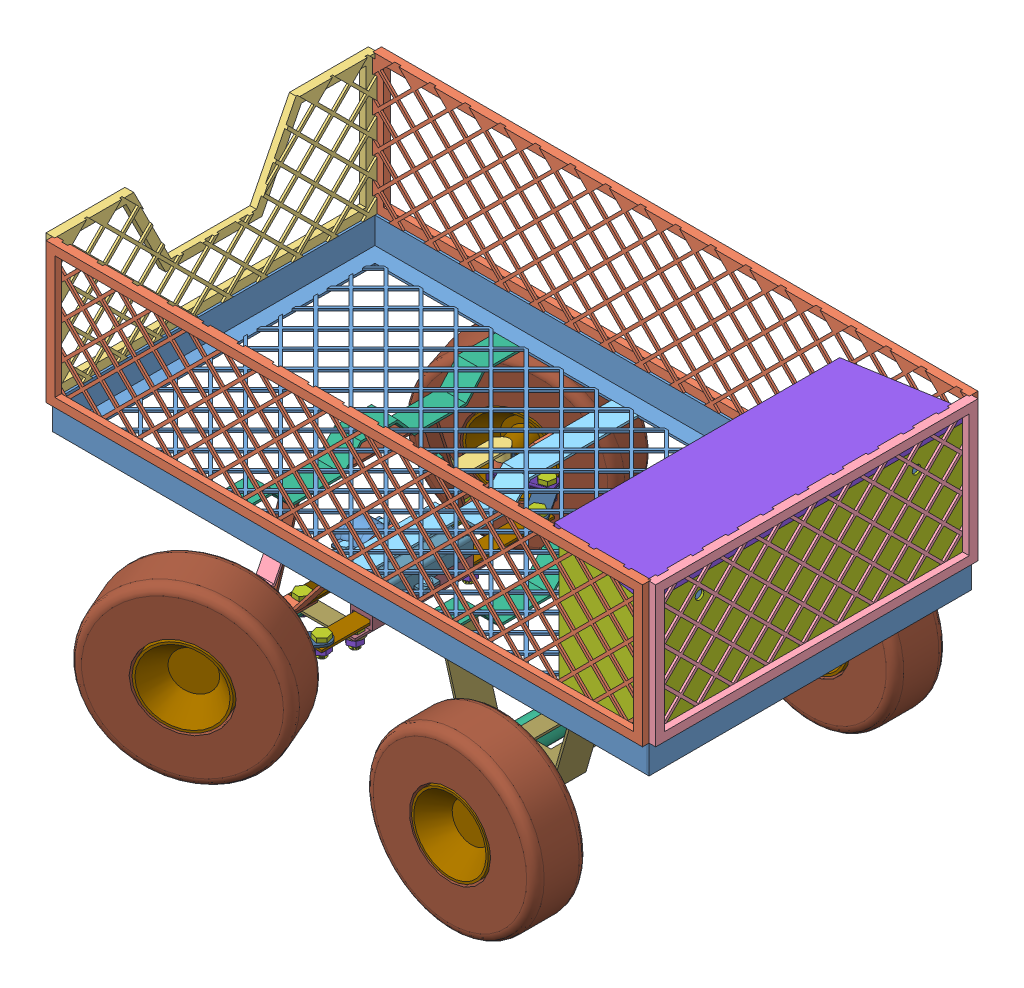
SolidWorks assembly BaseBot, configuration Default. Lengths in mm.
Overall size (882.65 573.45 703.44).
132 component instances, 48 part files, 93 mates.
Components (placement in the parent):
- Basket Bottom-1: Basket Bottom [Default] at (255.4338 0 27.1639) x (1 0 0) z (0 1 0) size (863.6 466.73 41.27)
- Basket Side-1: Basket Side [Default] at (387.544 20.0282 -463.55) x (0 0 -1) z (1 0 0) size (12.7 203.2 863.6)
- Basket Side-2: Basket Side [Default] at (213.6348 20.0282 -3.175) x (0 0 1) z (-1 0 0) size (12.7 203.2 863.6)
- Basket Front-2: Basket Front [Default] at (-128.0356 170.1145 -302.8358) x (-1 0 0) z (0 0 -1) size (12.7 203.2 466.73)
- Basket Back-1: Basket Back [Default] at (741.9144 37.962 -98.425) x (-1 0 0) z (0 0 1) size (12.7 203.2 466.73)
- BaseBot Support Bar #2-2: BaseBot Support Bar #2 [Default] at (237.0894 -11.8301 -299.0589) x (1 0 0) z (0 0 -1) size (38.1 28.57 419.1)
- BaseBot Support Bar #1-2: BaseBot Support Bar #1 [Default] at (68.8144 0 -270.0364) x (1 0 0) z (0 0 -1) size (38.1 32.02 419.1)
- BaseBot Support Bar #1-3: BaseBot Support Bar #1 [Default] at (370.4394 0 -270.0364) x (1 0 0) z (0 0 -1) size (38.1 32.02 419.1)
- BaseBot Support Bar #1-4: BaseBot Support Bar #1 [Default] at (579.9894 0 -270.0364) x (1 0 0) z (0 0 -1) size (38.1 32.02 419.1)
- Steering Mechanism-2: Steering Mechanism [Default] at (175.5898 -169.9237 -213.8762) x (0 0 -1) z (1 0 0) size (542.29 220.93 188.26)
  - Pinon Gear-1: Pinon Gear [Default] at (18.0596 23.4154 -25.5289) x (0.999971 0.007586 0) z (0 0 1) size (28.79 28.79 12.7)
  - 37d-gearmotor-100-131-150-encoder-1: 37d-gearmotor-100-131-150-encoder [Default] at (-1.8654 30.4154 -54.9751) size (36.8 36.8 90.1)
  - Rack-1: Rack [Default] at (-58.7281 -0.9127 -25.3751) x (0.965926 -0.258819 0) z (0 0 1) size (326.19 90.25 25.4)
  - Control Arm-1: Control Arm [Default] at (-149.1406 7.5404 -13.7125) x (-0.583389 0 0.812193) z (0 1 0) size (25.4 76.2 3.17)
  - Control Arm-2: Control Arm [Default] at (205.3106 7.5404 -41.201) x (-0.549424 0 -0.835544) z (0 1 0) size (25.4 76.2 3.17)
  - Front Wheel Bracket-1: Front Wheel Bracket [Default] at (7.9885 116.6287 -76.1751) x (1 0 0) z (0 0 -1) size (292.1 146.24 25.4)
  - Short Rack Support Structure-1: Short Rack Support Structure [Default] at (83.7255 -5.1596 -55.7455) x (-1 0 0) z (0 -1 0) size (25.4 101.6 3.17)
  - Short Rack Support Structure-2: Short Rack Support Structure [Default] at (-59.553 -5.1596 -45.8047) x (1 0 0) z (0 -1 0) size (25.4 101.6 3.17)
  - Long Rack Support Structure-2: Long Rack Support Structure [Default] at (-38.0612 -5.1596 -14.7918) x (0 1 0) z (1 0 0) size (26.76 57.15 190.5)
  - Long Rack Support Structure (Top)-1: Long Rack Support Structure (Top) [Default] at (37.6137 21.6016 3.1999) x (-1 0 0) z (0 0 -1) size (146.05 23.59 57.15)
  - Pivot Arm (Left)-2: Pivot Arm (Left) [Default] at (-186.8809 -11.5096 -33.1605) x (-0.541489 0 0.840708) z (-0.840708 0 -0.541489) size (96.16 53.98 123.84)
  - Pivot Arm (Right)-2: Pivot Arm (Right) [Default] at (211.0535 -8.3346 -33.1605) x (0.541489 0 0.840708) z (0.840708 0 -0.541489) size (104.82 53.97 137.29)
  - Front Wheel Axles-3: Front Wheel Axles [Default] at (277.9295 11.2102 -114.4995) x (-0.310493 0 -0.950576) z (-0.950576 0 0.310493) size (76.2 13.19 76.21)
  - Steering Motor Mount (Bottom)-2: Steering Motor Mount (Bottom) [Default] at (15.3381 12.3464 -101.5751) x (0 0 1) z (-1 0 0) size (78.58 31.27 183.81)
  - Steering Motor Mount (Top)-2: Steering Motor Mount (Top) [Default] at (19.4781 29.2864 -76.1751) x (0 0 -1) z (1 0 0) size (78.58 22.18 69.09)
  - Front Wheel Axles-4: Front Wheel Axles [Default] at (-240.1244 10.2206 -69.4744) x (-0.399781 0 -0.916611) z (0.916611 0 -0.399781) size (76.2 13.19 76.21)
  - Spacer-1: Spacer [Default] at (229.822 -8.3346 -95.0926) x (0.991664 0 -0.128853) z (0.128853 0 0.991664) size (19.05 12.7 19.05)
  - Spacer-2: Spacer [Default] at (-178.3747 -8.3346 -100.4751) x (0.523364 0 -0.852109) z (0.852109 0 0.523364) size (19.05 12.7 19.05)
  - Spacer-3: Spacer [Default] at (-169.1502 17.0654 -93.7664) size (19.05 12.7 19.05)
  - Spacer-4: Spacer [Default] at (230.5407 17.0654 -93.7664) size (19.05 12.7 19.05)
  - Front Wheel Support-1: Front Wheel Support [Default] at (127.4023 52.8952 -76.1751) x (-0.999975 0.007006 0) z (0 0 -1) size (101.09 57.73 25.4)
  - Front Wheel Support #2-1: Front Wheel Support #2 [Default] at (-103.2542 52.8183 -101.5751) x (0.999975 0.007006 0) z (0 0 1) size (85.09 57.73 25.4)
  - 0.25in Hex Bolt-1: 0.25in Hex Bolt [Default] at (1.5398 307.5194 143.5864) x (-0.430629 -0.859999 0.273788) z (0.894165 -0.447737 0) size (11.2 12.9 19.05)
  - 0.25in Hex Bolt-2: 0.25in Hex Bolt [Default] at (-17.0641 387.1538 -112.045) x (0.261641 -0.522518 -0.811491) z (-0.894165 -0.447737 0) size (11.2 12.9 19.05)
  - 0.25in Nut-1: 0.25in Nut [Default] at (125.0268 72.0692 -88.8751) x (0.297793 -0.594716 -0.746748) z (0.894165 0.447737 0) size (12.9 11.18 6.49)
  - 0.25in Nut-2: 0.25in Nut [Default] at (-101.1354 72.1209 -88.8751) x (0.403858 0.806536 0.431739) z (-0.894165 0.447737 0) size (12.9 11.18 6.49)
  - 0.25in Hex Bolt-3: 0.25in Hex Bolt [Default] at (-118.1926 35.6364 214.9281) x (-0.491617 0 -0.870811) z (0 -1 0) size (11.2 12.9 19.05)
  - 0.25in Hex Bolt-4: 0.25in Hex Bolt [Default] at (4.4078 28.1666 355.6025) x (-0.837169 0 -0.546944) z (0 -1 0) size (11.2 12.9 19.05)
  - 0.25in Hex Bolt-5: 0.25in Hex Bolt [Default] at (-36.5422 28.1666 311.1525) x (-0.837169 0 -0.546944) z (0 -1 0) size (11.2 12.9 19.05)
  - 0.25in Hex Bolt-6: 0.25in Hex Bolt [Default] at (-16.1952 35.6364 257.1775) x (-0.837169 0 -0.546944) z (0 -1 0) size (11.2 12.9 19.05)
  - 0.25in Hex Bolt-7: 0.25in Hex Bolt [Default] at (52.3578 28.1666 311.1525) x (-0.837169 0 -0.546944) z (0 -1 0) size (11.2 12.9 19.05)
  - 0.25in Nut-3: 0.25in Nut [Default] at (47.6747 21.5662 -88.8751) x (0.781177 0 -0.624309) z (0 1 0) size (12.9 11.18 6.49)
  - 0.25in Nut-4: 0.25in Nut [Default] at (59.8346 11.8571 -34.9001) x (1 0 0) z (0 1 0) size (12.9 11.18 6.49)
  - 0.25in Nut-5: 0.25in Nut [Default] at (11.8846 11.8554 9.5499) x (1 0 0) z (0 1 0) size (12.9 11.18 6.49)
  - 0.25in Nut-6: 0.25in Nut [Default] at (-29.0654 11.8571 -34.9001) x (1 0 0) z (0 1 0) size (12.9 11.18 6.49)
  - 0.25in Nut-7: 0.25in Nut [Default] at (-8.7184 21.5662 -88.8751) x (1 0 0) z (0 1 0) size (12.9 11.18 6.49)
  - 0.5in Hex Bolt-1: 0.5in Hex Bolt [Default] at (235.7047 23.4154 -40.5859) x (0.98122 0 0.192894) z (0 -1 0) size (22 19.05 28.57)
  - 0.5in Hex Bolt-2: 0.5in Hex Bolt [Default] at (193.2591 17.0654 -12.6751) x (1 0 0) z (0 -1 0) size (22 19.05 28.57)
  - 0.5in Hex Bolt-3: 0.5in Hex Bolt [Default] at (-70.3463 7.5404 -88.8751) x (-0.837169 0 -0.546944) z (0 -1 0) size (22 19.05 28.57)
  - 0.5in Hex Bolt-4: 0.5in Hex Bolt [Default] at (94.7596 4.3654 -12.6751) x (1 0 0) z (0 -1 0) size (22 19.05 28.57)
  - 0.5in Hex Bolt-5: 0.5in Hex Bolt [Default] at (94.7596 7.5404 -88.8751) x (0.964084 0 0.265597) z (0 -1 0) size (22 19.05 28.57)
  - 0.5in Hex Bolt-6: 0.5in Hex Bolt [Default] at (-70.3404 4.3654 -12.6751) x (0.999732 0 0.023139) z (0 -1 0) size (22 19.05 28.57)
  - 0.5in Hex Bolt-7: 0.5in Hex Bolt [Default] at (-118.1909 17.0654 -12.6751) x (0.969144 0 -0.246494) z (0 -1 0) size (22 19.05 28.57)
  - 0.5in Hex Bolt-8: 0.5in Hex Bolt [Default] at (-159.4503 23.4154 -42.3113) x (-0.837169 0 -0.546944) z (0 -1 0) size (22 19.05 28.57)
  - 0.5in Nut-1: 0.5in Nut [Default] at (193.2591 4.3654 -12.6751) x (1 0 0) z (0 -1 0) size (21.73 20.53 9.68)
  - 0.5in Nut-2: 0.5in Nut [Default] at (-159.4503 -5.1596 -42.3113) x (1 0 0) z (0 1 0) size (21.73 20.53 9.68)
  - 0.5in Nut-3: 0.5in Nut [Default] at (-70.3404 -17.8596 -12.6751) x (1 0 0) z (0 1 0) size (21.73 20.53 9.68)
  - 0.5in Nut-4: 0.5in Nut [Default] at (235.7047 -5.1596 -40.5859) x (1 0 0) z (0 1 0) size (21.73 20.53 9.68)
  - 0.5in Nut-5: 0.5in Nut [Default] at (94.7596 -21.0346 -88.8751) x (-0.015272 0 -0.999883) z (0 1 0) size (21.73 20.53 9.68)
  - 0.5in Nut-6: 0.5in Nut [Default] at (94.7596 -17.8596 -12.6751) x (1 0 0) z (0 1 0) size (21.73 20.53 9.68)
  - 0.5in Nut-7: 0.5in Nut [Default] at (-118.1909 4.3654 -12.6751) x (1 0 0) z (0 -1 0) size (21.73 20.53 9.68)
  - 0.5in Nut-8: 0.5in Nut [Default] at (-70.3463 -17.8596 -88.8751) x (1 0 0) z (0 1 0) size (21.73 20.53 9.68)
- Hub-10: Hub [Default] at (123.8857 -159.7031 66.9915) x (-0.399781 0 -0.916611) z (-0.916611 0 0.399781) size (88.9 111.12 111.12)
- Hub-11: Hub [Default] at (47.2889 -158.7135 -534.0588) x (0.310493 0 0.950576) z (-0.950576 0 0.310493) size (88.9 111.12 111.12)
- Radial Ball Bearing 17mm Bore-1: Radial Ball Bearing 17mm Bore [Default] at (74.8917 -158.7135 -449.5527) x (0 1 0) z (-0.950576 0 0.310493) size (34 12 34)
- Radial Ball Bearing 17mm Bore-2: Radial Ball Bearing 17mm Bore [Default] at (88.3451 -159.7031 -14.4951) x (0 -1 0) z (-0.916611 0 0.399781) size (34 12 34)
- Wheel-10: Wheel [Default] at (176.9035 -109.9016 43.8677) x (-0.399781 0 -0.916611) z (-0.91661 -0.000518 0.399781) size (76.2 247.65 247.65)
- Wheel-11: Wheel [Default] at (69.4962 -231.3772 -541.3125) x (0.310493 0 0.950576) z (-0.810689 0.522172 0.264801) size (76.2 247.65 247.65)
- Back Wheel Housing-4: Back Wheel Housing [Default] at (588.3026 -7.0122 -438.4176) x (-1 0 0) z (0 0 1) size (246.62 123.18 406.4)
- Gearbox-1: Gearbox [Default] at (568.39 -299.7014 -139.8553) x (-1 0 0) z (0 1 0) size (101.63 50.81 63.71)
  - Gearbox Bottom-1: Gearbox Bottom [Default] at (74.587 76.0877 168.5715) size (101.6 28.57 63.5)
  - Gearbox - 12T-1: Gearbox - 12T [Default] at (92.1067 91.9627 143.3599) x (0.92261 0 -0.385735) z (0 1 0) size (23.03 23.03 12.7)
  - Gearbox - 24T-1: Gearbox - 24T [Default] at (61.1138 91.9627 144.7723) x (1 0 0) z (0 1 0) size (43.72 43.72 12.7)
  - Gearbox - 12T-2: Gearbox - 12T [Default] at (122.4014 91.9627 144.7942) x (1 0 0) z (0 -1 0) size (23.03 23.03 12.7)
  - Gearbox - 24T-2: Gearbox - 24T [Default] at (92.1067 79.2627 143.3599) x (0.834365 0 -0.551212) z (0 1 0) size (43.72 43.72 12.7)
  - R155-2RS Mini ball Bearing-1: R155-2RS Mini ball Bearing [Default] at (92.1067 95.0377 143.3599) x (1 0 0) z (0 0 -1) size (7.94 3.17 7.94)
  - R155-2RS Mini ball Bearing-2: R155-2RS Mini ball Bearing [Default] at (61.1138 95.0377 144.7723) x (1 0 0) z (0 0 -1) size (7.94 3.17 7.94)
  - R155-2RS Mini ball Bearing-3: R155-2RS Mini ball Bearing [Default] at (92.1067 104.7627 143.3599) x (0.999892 0 0.014713) z (0.014713 0 -0.999892) size (7.94 3.17 7.94)
  - R155-2RS Mini ball Bearing-4: R155-2RS Mini ball Bearing [Default] at (61.1138 104.7627 144.7723) x (1 0 0) z (0 0 -1) size (7.94 3.17 7.94)
  - R155-2RS Mini ball Bearing-5: R155-2RS Mini ball Bearing [Default] at (122.4014 79.1627 144.7942) size (7.94 3.17 7.94)
  - R155-2RS Mini ball Bearing-6: R155-2RS Mini ball Bearing [Default] at (92.1067 82.3377 143.3599) x (1 0 0) z (0 0 -1) size (7.94 3.17 7.94)
  - R155-2RS Mini ball Bearing-7: R155-2RS Mini ball Bearing [Default] at (122.4014 92.0627 144.7942) x (1 0 0) z (0 0 -1) size (7.94 3.17 7.94)
  - R155-2RS Mini ball Bearing-8: R155-2RS Mini ball Bearing [Default] at (92.1067 92.0627 143.3599) x (1 0 0) z (0 0 -1) size (7.94 3.17 7.94)
  - 2in Axle-2: 2in Axle [Default] at (122.4014 104.655 144.7942) x (0.232669 0 0.972556) z (0 -1 0) size (3.97 3.97 38.1)
  - 2in Axle-3: 2in Axle [Default] at (61.1138 79.2627 144.7723) x (0.898573 0 0.438824) z (0 1 0) size (3.97 3.97 38.1)
  - 1in Axle-1: 1in Axle [Default] at (92.1067 79.2627 143.3599) x (0.237926 0 -0.971283) z (0 1 0) size (3.97 3.97 25.4)
  - Gearbox Lid-1: Gearbox Lid [Default] at (121.6136 104.6627 145.3537) x (1 0 0) z (0 1 0) size (101.6 63.5 3.17)
  - 0.25in Hex Bolt-1: 0.25in Hex Bolt [Default] at (121.2528 111.0127 514.2191) x (-0.837169 0 -0.546944) z (0 -1 0) size (11.2 12.9 19.05)
  - 0.25in Hex Bolt-2: 0.25in Hex Bolt [Default] at (36.3678 111.0127 467.4391) x (-0.837169 0 -0.546944) z (0 -1 0) size (11.2 12.9 19.05)
- Front Wheel Brace-1: Front Wheel Brace [Default] at (133.8633 -17.6291 -360.0687) x (0 0 1) z (1 0 0) size (25.4 171.49 182.31)
- Front Wheel Brace-2: Front Wheel Brace [Default] at (133.8633 -17.6291 -135.4151) x (0 0 1) z (1 0 0) size (25.4 171.49 182.31)
- 37d-gearmotor-100-131-150-encoder-2: 37d-gearmotor-100-131-150-encoder [Default] at (425.8036 -148.6967 -112.0426) x (0.999225 0.039351 0) z (0 0 1) size (36.8 36.8 90.1)
- Motor to Axle Adapter-2: Motor to Axle Adapter [Default] at (445.9886 -154.9072 -70.1176) x (-0.999225 -0.039351 0) z (0 0 -1) size (12.34 12.34 19.05)
- Wheel to Axle Adapter-2: Wheel to Axle Adapter [Default] at (507.2762 -154.9291 -32.0176) x (-0.979173 -0.203029 0) z (0 0 1) size (14.7 14.7 50.8)
- Gearbox-3: Gearbox [Default] at (568.39 -10.1486 -330.5799) x (-1 0 0) z (0 -1 0) size (101.63 50.81 63.71)
  - Gearbox Bottom-1: Gearbox Bottom [Default] at (74.587 76.0877 168.5715) size (101.6 28.57 63.5)
  - Gearbox - 12T-1: Gearbox - 12T [Default] at (92.1067 91.9627 143.3599) x (0.92261 0 -0.385735) z (0 1 0) size (23.03 23.03 12.7)
  - Gearbox - 24T-1: Gearbox - 24T [Default] at (61.1138 91.9627 144.7723) x (1 0 0) z (0 1 0) size (43.72 43.72 12.7)
  - Gearbox - 12T-2: Gearbox - 12T [Default] at (122.4014 91.9627 144.7942) x (1 0 0) z (0 -1 0) size (23.03 23.03 12.7)
  - Gearbox - 24T-2: Gearbox - 24T [Default] at (92.1067 79.2627 143.3599) x (0.834365 0 -0.551212) z (0 1 0) size (43.72 43.72 12.7)
  - R155-2RS Mini ball Bearing-1: R155-2RS Mini ball Bearing [Default] at (92.1067 95.0377 143.3599) x (1 0 0) z (0 0 -1) size (7.94 3.17 7.94)
  - R155-2RS Mini ball Bearing-2: R155-2RS Mini ball Bearing [Default] at (61.1138 95.0377 144.7723) x (1 0 0) z (0 0 -1) size (7.94 3.17 7.94)
  - R155-2RS Mini ball Bearing-3: R155-2RS Mini ball Bearing [Default] at (92.1067 104.7627 143.3599) x (0.999892 0 0.014713) z (0.014713 0 -0.999892) size (7.94 3.17 7.94)
  - R155-2RS Mini ball Bearing-4: R155-2RS Mini ball Bearing [Default] at (61.1138 104.7627 144.7723) x (1 0 0) z (0 0 -1) size (7.94 3.17 7.94)
  - R155-2RS Mini ball Bearing-5: R155-2RS Mini ball Bearing [Default] at (122.4014 79.1627 144.7942) size (7.94 3.17 7.94)
  - R155-2RS Mini ball Bearing-6: R155-2RS Mini ball Bearing [Default] at (92.1067 82.3377 143.3599) x (1 0 0) z (0 0 -1) size (7.94 3.17 7.94)
  - R155-2RS Mini ball Bearing-7: R155-2RS Mini ball Bearing [Default] at (122.4014 92.0627 144.7942) x (1 0 0) z (0 0 -1) size (7.94 3.17 7.94)
  - R155-2RS Mini ball Bearing-8: R155-2RS Mini ball Bearing [Default] at (92.1067 92.0627 143.3599) x (1 0 0) z (0 0 -1) size (7.94 3.17 7.94)
  - 2in Axle-2: 2in Axle [Default] at (122.4014 104.655 144.7942) x (0.232669 0 0.972556) z (0 -1 0) size (3.97 3.97 38.1)
  - 2in Axle-3: 2in Axle [Default] at (61.1138 79.2627 144.7723) x (0.898573 0 0.438824) z (0 1 0) size (3.97 3.97 38.1)
  - 1in Axle-1: 1in Axle [Default] at (92.1067 79.2627 143.3599) x (0.237926 0 -0.971283) z (0 1 0) size (3.97 3.97 25.4)
  - Gearbox Lid-1: Gearbox Lid [Default] at (121.6136 104.6627 145.3537) x (1 0 0) z (0 1 0) size (101.6 63.5 3.17)
  - 0.25in Hex Bolt-1: 0.25in Hex Bolt [Default] at (121.2528 111.0127 514.2191) x (-0.837169 0 -0.546944) z (0 -1 0) size (11.2 12.9 19.05)
  - 0.25in Hex Bolt-2: 0.25in Hex Bolt [Default] at (36.3678 111.0127 467.4391) x (-0.837169 0 -0.546944) z (0 -1 0) size (11.2 12.9 19.05)
- Motor to Axle Adapter-4: Motor to Axle Adapter [Default] at (445.9886 -154.9428 -400.3176) x (0.99689 0.078808 0) z (0 0 1) size (12.34 12.34 19.05)
- Wheel to Axle Adapter-3: Wheel to Axle Adapter [Default] at (507.2762 -154.9209 -438.4176) x (-0.879655 -0.475613 0) z (0 0 -1) size (14.7 14.7 50.8)
- 37d-gearmotor-100-131-150-encoder-4: 37d-gearmotor-100-131-150-encoder [Default] at (465.6274 -147.176 -358.3236) x (-0.999249 -0.038749 0) z (0 0 -1) size (36.8 36.8 90.1)
- Hub-12: Hub [Default] at (507.2762 -154.9291 63.2324) x (0 0 -1) z (0.923728 0.383049 0) size (88.9 111.12 111.12)
- Hub-14: Hub [Default] at (507.2762 -154.9209 -533.6676) x (0 0 1) z (-0.923728 -0.383049 0) size (88.9 111.12 111.12)
- Radial Ball Bearing 17mm Bore-3: Radial Ball Bearing 17mm Bore [Default] at (507.2762 -154.9291 -25.6676) x (0.383049 -0.923728 0) z (-0.923728 -0.383049 0) size (34 12 34)
- Radial Ball Bearing 17mm Bore-4: Radial Ball Bearing 17mm Bore [Default] at (507.2762 -154.9209 -444.7676) x (-0.383049 0.923728 0) z (-0.923728 -0.383049 0) size (34 12 34)
- Wheel-12: Wheel [Default] at (557.4681 -97.4263 63.2324) x (0 0 -1) z (-0.989814 -0.142364 0) size (76.2 247.65 247.65)
- Wheel-13: Wheel [Default] at (579.7945 -178.7304 -533.6676) x (0 0 1) z (-0.923728 -0.383049 0) size (76.2 247.65 247.65)
- Back Motor Housing-1: Back Motor Housing [Default] at (450.0429 -135.0507 -328.9985) x (-1 0 0) z (0 0 -1) size (46.63 44.52 88.17)
- Back Motor Housing #2-1: Back Motor Housing #2 [Default] at (450.0429 -135.0507 -105.7116) x (-1 0 0) z (0 0 -1) size (46.63 44.52 88.17)
- Electronic Housing-1: Electronic Housing [Default] at (560.0657 6.35 -82.9961) x (0 1 0) z (0 0 -1) size (206.38 152.4 466.73)
- Electronic Housing  Lid-1: Electronic Housing  Lid [Default] at (654.5068 222.725 -248.6086) x (0 0 -1) z (-1 0 0) size (466.73 22.7 160.75)
- IMU Mount-1: IMU Mount [Default] at (620.5602 9.525 -235.0978) size (26.67 9.53 20.32)
- Mighty Max Battery 12V-1: Mighty Max Battery 12V [Default] at (734.3012 9.525 -312.8809) x (0 0 1) z (-1 0 0) size (181.1 166.88 76.45)
- Raspberry Pi Mount-1: Raspberry Pi Mount [Default] at (601.2449 9.525 -363.4658) x (0 1 0) z (0 0 1) size (15.88 49 85)
- Mighty Max Battery 12V-2: Mighty Max Battery 12V [Default] at (734.3012 9.525 -116.8985) x (0 0 1) z (-1 0 0) size (181.1 166.88 76.45)
- HBridge Mount-1: HBridge Mount [Default] at (610.79 9.525 -158.1025) x (0 0 -1) z (1 0 0) size (100 33.18 50)
Mates (geometry in assembly coordinates):
- Coincident4: coincident anti-aligned: plane of Basket Bottom-1 through (729.2144 41.275 -466.725) normal (0 1 0); plane of Basket Side-1 through (732.3894 41.275 -476.25) normal (0 -1 0)
- Coincident6: coincident aligned: plane of Basket Bottom-1 through (732.3894 3.175 -466.725) normal (1 0 0); plane of Basket Side-1 through (732.3894 244.475 -476.25) normal (1 0 0)
- Coincident7: coincident: line of Basket Bottom-1 through (-128.0356 41.275 -463.55) axis (1 0 0); plane of Basket Side-1 through (387.544 20.0282 -463.55) normal (0 0 1)
- Coincident8: coincident anti-aligned: plane of Basket Bottom-1 through (729.2144 41.275 -466.725) normal (0 1 0); plane of Basket Side-2 through (-131.2106 41.275 9.525) normal (0 -1 0)
- Coincident9: coincident aligned: plane of Basket Bottom-1 through (732.3894 3.175 -466.725) normal (1 0 0); plane of Basket Side-2 through (732.3894 244.475 9.525) normal (1 0 0)
- Coincident10: coincident: line of Basket Bottom-1 through (729.2144 41.275 -3.175) axis (-1 0 0); plane of Basket Side-2 through (213.6348 20.0282 -3.175) normal (0 0 -1)
- Coincident11: coincident anti-aligned: plane of Basket Bottom-1 through (729.2144 41.275 -466.725) normal (0 1 0); plane of Basket Front-2 through (-140.7356 41.275 0) normal (0 -1 0)
- Coincident12: coincident aligned: plane of Basket Bottom-1 through (-131.2106 3.175 0) normal (0 0 1); plane of Basket Front-2 through (-140.7356 244.475 0) normal (0 0 1)
- Coincident13: coincident: line of Basket Bottom-1 through (-128.0356 41.275 -3.175) axis (0 0 -1); plane of Basket Front-2 through (-128.0356 170.1145 -302.8358) normal (1 0 0)
- Coincident22: coincident anti-aligned: plane of Basket Bottom-1 through (729.2144 41.275 -466.725) normal (0 1 0); plane of Basket Back-1 through (729.2144 41.275 0) normal (0 -1 0)
- Coincident23: coincident aligned: plane of Basket Bottom-1 through (-131.2106 3.175 -466.725) normal (0 0 -1); plane of Basket Back-1 through (729.2144 41.275 -466.725) normal (0 0 -1)
- Coincident24: coincident: line of Basket Bottom-1 through (729.2144 41.275 -463.55) axis (0 0 1); plane of Basket Back-1 through (729.2144 37.962 -98.425) normal (-1 0 0)
- Parallel63: parallel aligned: plane of Basket Bottom-1 through (732.3894 3.175 -466.725) normal (1 0 0); plane of Basket Side-1 through (387.544 20.0282 -463.55) normal (1 0 0)
- Coincident313: coincident aligned: plane of Basket Bottom-1 through (-131.2106 3.175 0) normal (0 0 1)
- Coincident322: coincident: point of BaseBot Support Bar #2-2
- Coincident323: coincident: unknown of BaseBot Support Bar #1-2
- Coincident326: coincident: unknown of BaseBot Support Bar #1-3
- Coincident329: coincident: unknown of BaseBot Support Bar #1-4
- Coincident331: coincident anti-aligned: plane of Basket Bottom-1 through (255.4338 0 27.1639) normal (0 -1 0)
- Parallel69: parallel aligned: line of Basket Bottom-1 through (706.9894 0 -441.325) axis (-1 0 0); line of BaseBot Support Bar #1-4 through (618.0894 0 -444.5) axis (-1 0 0)
- Parallel70: parallel aligned: line of Basket Bottom-1 through (706.9894 0 -441.325) axis (-1 0 0); line of BaseBot Support Bar #1-3 through (408.5394 0 -444.5) axis (-1 0 0)
- Parallel71: parallel aligned: line of Basket Bottom-1 through (706.9894 0 -441.325) axis (-1 0 0); line of BaseBot Support Bar #2-2 through (275.1894 0 -444.5) axis (-1 0 0)
- Parallel72: parallel aligned: line of Basket Bottom-1 through (706.9894 0 -441.325) axis (-1 0 0); line of BaseBot Support Bar #1-2 through (106.9144 0 -444.5) axis (-1 0 0)
- Coincident336: coincident anti-aligned: plane of BaseBot Support Bar #1-2 through (106.9144 -28.8441 -184.15) normal (0 -1 0); plane of Steering Mechanism-2/Front Wheel Bracket-1 through (74.0147 -28.8441 -125.95) normal (0 1 0)
- Parallel73: parallel anti-aligned: line of BaseBot Support Bar #1-2 through (106.9144 -28.8441 -107.95) axis (0 0 -1); line of Steering Mechanism-2/Long Rack Support Structure (Top)-1 through (178.7897 -129.7321 -299.1108) axis (0 0 1)
- Coincident338: coincident: unknown of Steering Mechanism-2/Front Wheel Bracket-1
- Concentric1: concentric aligned: cylinder of Hub-10 through (93.4223 -159.7031 -2.8542) axis (0.399781 0 0.916611) radius 55.5625; cylinder of Wheel-10 through (93.4223 -159.7031 -2.8542) axis (0.399781 0 0.916611) radius 58.7375
- Coincident339: coincident aligned: plane of Hub-10 through (123.8857 -159.7031 66.9915) normal (0.399781 0 0.916611); plane of Wheel-10 through (123.8857 -159.7031 66.9915) normal (0.399781 0 0.916611)
- Concentric2: concentric anti-aligned: cylinder of Hub-10 through (88.3451 -159.7031 -14.4951) axis (0.399781 0 0.916611) radius 17; cylinder of Radial Ball Bearing 17mm Bore-2 through (93.1425 -159.7031 -3.4958) axis (-0.399781 0 -0.916611) radius 17
- Coincident340: coincident aligned: plane of Hub-10 through (88.3451 -159.7031 -14.4951) normal (-0.399781 0 -0.916611); plane of Radial Ball Bearing 17mm Bore-2 through (88.3451 -159.7031 -14.4951) normal (-0.399781 0 -0.916611)
- Concentric3: concentric aligned: cylinder of Hub-11 through (70.9485 -158.7135 -461.625) axis (-0.310493 0 -0.950576) radius 55.5625; cylinder of Wheel-11 through (70.9485 -158.7135 -461.625) axis (-0.310493 0 -0.950576) radius 58.7375
- Coincident341: coincident aligned: plane of Hub-11 through (47.2889 -158.7135 -534.0588) normal (-0.310493 0 -0.950576); plane of Wheel-11 through (47.2889 -158.7135 -534.0588) normal (-0.310493 0 -0.950576)
- Concentric4: concentric anti-aligned: cylinder of Hub-11 through (74.8917 -158.7135 -449.5527) axis (-0.310493 0 -0.950576) radius 17; cylinder of Radial Ball Bearing 17mm Bore-1 through (71.1658 -158.7135 -460.9596) axis (0.310493 0 0.950576) radius 17
- Coincident342: coincident aligned: plane of Hub-11 through (74.8917 -158.7135 -449.5527) normal (0.310493 0 0.950576); plane of Radial Ball Bearing 17mm Bore-1 through (74.8917 -158.7135 -449.5527) normal (0.310493 0 0.950576)
- Concentric5: concentric anti-aligned: cylinder of Steering Mechanism-2/Front Wheel Axles-4 through (85.8065 -159.7031 -20.3156) axis (0.399781 0 0.916611) radius 6.35; cylinder of Radial Ball Bearing 17mm Bore-2 through (93.1425 -159.7031 -3.4958) axis (-0.399781 0 -0.916611) radius 6.35
- Concentric6: concentric anti-aligned: cylinder of Steering Mechanism-2/Front Wheel Axles-3 through (76.8633 -158.7135 -443.5165) axis (-0.310493 0 -0.950576) radius 6.35; cylinder of Radial Ball Bearing 17mm Bore-1 through (71.1658 -158.7135 -460.9596) axis (0.310493 0 0.950576) radius 6.35
- Coincident344: coincident anti-aligned: plane of Steering Mechanism-2/Front Wheel Axles-3 through (61.0903 -158.7135 -491.8057) normal (-0.310493 0 -0.950576); plane of Hub-11 through (61.0903 -158.7135 -491.8057) normal (0.310493 0 0.950576)
- Coincident345: coincident aligned: circle of Steering Mechanism-2/Front Wheel Axles-4; plane of Hub-10 through (106.1154 -159.7031 26.2482) normal (-0.399781 0 -0.916611)
- Coincident348: coincident anti-aligned: plane of BaseBot Support Bar #1-4 through (618.0894 0 -444.5) normal (0 -1 0); plane of Back Wheel Housing-4 through (618.0894 0 -387.6176) normal (0 1 0)
- Coincident349: coincident aligned: line of BaseBot Support Bar #1-4 through (618.0894 0 -387.35) axis (0 0 -1); line of Back Wheel Housing-4 through (618.0894 0 -387.6176) axis (0 0 -1)
- Coincident355: coincident aligned: line of Back Wheel Housing-4 through (431.2799 -123.175 -32.0176) axis (0 0 -1); line of Gearbox-1/Gearbox Bottom-1 through (431.2799 -123.175 -35.1926) axis (0 0 -1)
- Coincident357: coincident anti-aligned: plane of Back Wheel Housing-4 through (558.2799 -123.175 -387.6176) normal (0 -1 0); plane of Gearbox-1/Gearbox Bottom-1 through (532.8799 -123.175 -60.5926) normal (0 1 0)
- Coincident358: coincident anti-aligned: line of Back Wheel Housing-4 through (431.2799 -123.175 -32.0176) axis (1 0 0); line of Gearbox-1/Gearbox Lid-1 through (532.9055 -123.175 -32.0176) axis (-1 0 0)
- Coincident364: coincident anti-aligned: plane of Steering Mechanism-2/Front Wheel Bracket-1 through (74.0147 -171.9083 -221.8647) normal (0 1 0); plane of Front Wheel Brace-1 through (99.4147 -171.9083 -334.6687) normal (0 -1 0)
- Parallel75: parallel anti-aligned: line of Steering Mechanism-2/Front Wheel Bracket-1 through (74.0147 -171.9083 -367.9797) axis (0 0 1); line of Front Wheel Brace-1 through (74.0147 -168.7333 -334.6687) axis (0 0 -1)
- Coincident366: coincident anti-aligned: line of Steering Mechanism-2/Front Wheel Bracket-1 through (74.0147 -171.9083 -367.9797) axis (0 0 1); line of Front Wheel Brace-1 through (74.0147 -171.9083 -334.6687) axis (0 0 -1)
- Coincident367: coincident anti-aligned: plane of Steering Mechanism-2/Front Wheel Bracket-1 through (74.0147 -171.9083 -221.8647) normal (0 1 0); plane of Front Wheel Brace-2 through (99.4147 -171.9083 -110.0151) normal (0 -1 0)
- Parallel76: parallel anti-aligned: line of Steering Mechanism-2/Front Wheel Bracket-1 through (74.0147 -171.9083 -152.9392) axis (0 0 1); line of Front Wheel Brace-2 through (74.0147 -168.7333 -110.0151) axis (0 0 -1)
- Coincident369: coincident anti-aligned: line of Steering Mechanism-2/Front Wheel Bracket-1 through (74.0147 -171.9083 -152.9392) axis (0 0 1); line of Front Wheel Brace-2 through (74.0147 -171.9083 -110.0151) axis (0 0 -1)
- Concentric8: concentric anti-aligned: cylinder of 37d-gearmotor-100-131-150-encoder-2 through (445.9886 -154.9072 -70.1176) axis (0 0 -1) radius 3; cylinder of Motor to Axle Adapter-2 through (445.9886 -154.9072 -82.8176) axis (0 0 1) radius 2.9972
- Parallel77: parallel anti-aligned: plane of 37d-gearmotor-100-131-150-encoder-2 through (445.8942 -152.5091 -82.1176) normal (-0.039351 0.999225 0); plane of Motor to Axle Adapter-2 through (445.8944 -152.5151 -82.8176) normal (0.039351 -0.999225 0)
- Coincident376: coincident aligned: plane of 37d-gearmotor-100-131-150-encoder-2 through (445.9886 -154.9072 -70.1176) normal (0 0 1); circle of Motor to Axle Adapter-2
- Concentric10: concentric anti-aligned: cylinder of Gearbox-1/2in Axle-2 through (445.9886 -154.9072 -73.3003) axis (0 0 1) radius 1.9844; cylinder of Motor to Axle Adapter-2 through (445.9886 -154.9072 -63.7676) axis (0 0 -1) radius 1.985
- Coincident378: coincident anti-aligned: plane of Gearbox-1/Gearbox Bottom-1 through (493.803 -131.1299 -63.7676) normal (0 0 -1); plane of Motor to Axle Adapter-2 through (445.9886 -154.9072 -63.7676) normal (0 0 1)
- Concentric15: concentric aligned: cylinder of Gearbox-1/2in Axle-3 through (507.2762 -154.9291 -22.4926) axis (0 0 -1) radius 1.9844; cylinder of Wheel to Axle Adapter-2 through (507.2762 -154.9291 -25.6676) axis (0 0 -1) radius 1.985
- Coincident388: coincident anti-aligned: plane of Gearbox-1/Gearbox Lid-1 through (446.7764 -154.3477 -32.0176) normal (0 0 1); plane of Wheel to Axle Adapter-2 through (507.2762 -154.9291 -32.0176) normal (0 0 -1)
- Coincident394: coincident anti-aligned: plane of Back Wheel Housing-4 through (558.2799 -123.175 -387.6176) normal (0 -1 0); plane of Gearbox-3/Gearbox Bottom-1 through (532.8799 -123.175 -409.8426) normal (0 1 0)
- Coincident395: coincident aligned: line of Back Wheel Housing-4 through (431.2799 -123.175 -438.4176) axis (1 0 0); line of Gearbox-3/Gearbox Lid-1 through (431.3055 -123.175 -438.4176) axis (1 0 0)
- Coincident396: coincident anti-aligned: line of Back Wheel Housing-4 through (431.2799 -123.175 -387.6176) axis (0 0 -1); line of Gearbox-3/Gearbox Bottom-1 through (431.2799 -123.175 -435.2426) axis (0 0 1)
- Concentric17: concentric anti-aligned: cylinder of Gearbox-3/2in Axle-2 through (445.9886 -154.9428 -397.1349) axis (0 0 -1) radius 1.9844; cylinder of Motor to Axle Adapter-4 through (445.9886 -154.9428 -406.6676) axis (0 0 1) radius 1.985
- Coincident397: coincident anti-aligned: plane of Gearbox-3/Gearbox Bottom-1 through (493.803 -178.7201 -406.6676) normal (0 0 1); plane of Motor to Axle Adapter-4 through (445.9886 -154.9428 -406.6676) normal (0 0 -1)
- Concentric18: concentric aligned: cylinder of Gearbox-3/2in Axle-3 through (507.2762 -154.9209 -447.9426) axis (0 0 1) radius 1.9844; cylinder of Wheel to Axle Adapter-3 through (507.2762 -154.9209 -444.7676) axis (0 0 1) radius 1.985
- Coincident398: coincident anti-aligned: plane of Gearbox-3/Gearbox Lid-1 through (446.7764 -155.5023 -438.4176) normal (0 0 -1); plane of Wheel to Axle Adapter-3 through (507.2762 -154.9209 -438.4176) normal (0 0 1)
- Concentric20: concentric anti-aligned: cylinder of Motor to Axle Adapter-4 through (445.9886 -154.9428 -387.6176) axis (0 0 -1) radius 2.9972; cylinder of 37d-gearmotor-100-131-150-encoder-4 through (445.9886 -154.9428 -400.2486) axis (0 0 1) radius 3
- Concentric21: concentric aligned: cylinder of Hub-12 through (507.2762 -154.9291 -12.9676) axis (0 0 1) radius 55.5625; cylinder of Wheel-12 through (507.2762 -154.9291 -12.9676) axis (0 0 1) radius 58.7375
- Coincident401: coincident aligned: plane of Hub-12 through (507.2762 -154.9291 63.2324) normal (0 0 1); plane of Wheel-12 through (507.2762 -154.9291 63.2324) normal (0 0 1)
- Concentric22: concentric anti-aligned: cylinder of Hub-12 through (507.2762 -154.9291 -25.6676) axis (0 0 1) radius 17; cylinder of Radial Ball Bearing 17mm Bore-3 through (507.2762 -154.9291 -13.6676) axis (0 0 -1) radius 17
- Coincident402: coincident aligned: circle of Hub-12; plane of Radial Ball Bearing 17mm Bore-3 through (507.2762 -154.9291 -25.6676) normal (0 0 -1)
- Concentric23: concentric aligned: cylinder of Wheel to Axle Adapter-2 through (507.2762 -154.9291 18.7824) axis (0 0 -1) radius 7.35; cylinder of Radial Ball Bearing 17mm Bore-3 through (507.2762 -154.9291 -13.6676) axis (0 0 -1) radius 6.35
- Coincident403: coincident anti-aligned: plane of Wheel to Axle Adapter-2 through (507.2762 -154.9291 18.7824) normal (0 0 1); plane of Hub-12 through (507.2762 -154.9291 18.7824) normal (0 0 -1)
- Concentric24: concentric anti-aligned: cylinder of Hub-14 through (507.2762 -154.9209 -444.7676) axis (0 0 -1) radius 17; cylinder of Radial Ball Bearing 17mm Bore-4 through (507.2762 -154.9209 -456.7676) axis (0 0 1) radius 17
- Coincident404: coincident aligned: plane of Hub-14 through (507.2762 -154.9209 -444.7676) normal (0 0 1); plane of Radial Ball Bearing 17mm Bore-4 through (507.2762 -154.9209 -444.7676) normal (0 0 1)
- Concentric25: concentric aligned: cylinder of Hub-14 through (507.2762 -154.9209 -457.4676) axis (0 0 -1) radius 55.5625; cylinder of Wheel-13 through (507.2762 -154.9209 -457.4676) axis (0 0 -1) radius 58.7375
- Coincident405: coincident aligned: plane of Hub-14 through (507.2762 -154.9209 -533.6676) normal (0 0 -1); plane of Wheel-13 through (507.2762 -154.9209 -533.6676) normal (0 0 -1)
- Concentric28: concentric aligned: cylinder of Wheel to Axle Adapter-3 through (507.2762 -154.9209 -489.2176) axis (0 0 1) radius 7.35; cylinder of Radial Ball Bearing 17mm Bore-4 through (507.2762 -154.9209 -456.7676) axis (0 0 1) radius 6.35
- Coincident407: coincident anti-aligned: plane of Wheel to Axle Adapter-3 through (507.2762 -154.9209 -489.2176) normal (0 0 -1); plane of Hub-14 through (507.2762 -154.9209 -489.2176) normal (0 0 1)
- Coincident410: coincident anti-aligned: plane of Back Wheel Housing-4 through (558.2799 -123.175 -387.6176) normal (0 -1 0); plane of Back Motor Housing-1 through (450.0429 -123.175 -367.0985) normal (0 1 0)
- Coincident411: coincident anti-aligned: line of Back Wheel Housing-4 through (456.6799 -123.175 -82.8176) axis (0 0 -1); line of Back Motor Housing-1 through (456.6799 -123.175 -367.0985) axis (0 0 1)
- Coincident412: coincident: plane of Back Wheel Housing-4 through (558.2799 -123.175 -387.6176) normal (0 -1 0); plane of Back Motor Housing #2-1 through (450.0429 -123.175 -143.8116) normal (0 1 0)
- Coincident413: coincident anti-aligned: line of Back Wheel Housing-4 through (456.6799 -123.175 -82.8176) axis (0 0 -1); line of Back Motor Housing #2-1 through (456.6799 -123.175 -143.8116) axis (0 0 1)
- Coincident414: coincident: plane of Basket Bottom-1 through (255.4338 6.35 27.1639) normal (0 1 0); plane of Electronic Housing-1 through (560.0657 6.35 -82.9961) normal (0 -1 0)
- Coincident415: coincident anti-aligned: plane of Basket Back-1 through (729.2144 37.962 -98.425) normal (-1 0 0); plane of Electronic Housing-1 through (729.2144 9.525 -466.7129) normal (1 0 0)
- Coincident419: coincident: plane of Electronic Housing-1 through (726.0394 212.725 -3.7359) normal (-1 0 0); plane of Mighty Max Battery 12V-2 through (726.0394 176.403 -228.1723) normal (1 0 0)
- Coincident420: coincident anti-aligned: plane of Electronic Housing-1 through (560.0657 9.525 -82.9961) normal (0 1 0); plane of Mighty Max Battery 12V-2 through (734.3012 9.525 -116.8985) normal (0 -1 0)
- Coincident421: coincident: plane of Electronic Housing-1 through (726.0394 212.725 -3.7359) normal (-1 0 0); plane of Mighty Max Battery 12V-1 through (726.0394 176.403 -424.1547) normal (1 0 0)
- Coincident422: coincident anti-aligned: plane of Electronic Housing-1 through (560.0657 9.525 -82.9961) normal (0 1 0); plane of Mighty Max Battery 12V-1 through (734.3012 9.525 -312.8809) normal (0 -1 0)
- Coincident423: coincident anti-aligned: plane of Electronic Housing-1 through (560.0657 9.525 -82.9961) normal (0 1 0); plane of IMU Mount-1 through (620.5602 9.525 -235.0978) normal (0 -1 0)
- Coincident424: coincident anti-aligned: plane of Electronic Housing-1 through (560.0657 9.525 -82.9961) normal (0 1 0); plane of Raspberry Pi Mount-1 through (601.2449 9.525 -363.4658) normal (0 -1 0)
- Coincident425: coincident anti-aligned: plane of Electronic Housing-1 through (560.0657 212.725 -82.9961) normal (0 1 0); plane of Electronic Housing  Lid-1 through (654.5068 212.725 -248.6086) normal (0 -1 0)
- Parallel81: parallel aligned: line of Electronic Housing-1 through (729.2144 212.725 0.0121) axis (0 0 -1); line of Electronic Housing  Lid-1 through (729.2144 222.725 -0.073) axis (0 0 -1)
- Coincident427: coincident aligned: line of Electronic Housing-1 through (729.2144 212.725 0.0121) axis (0 0 -1); line of Electronic Housing  Lid-1 through (729.2144 212.725 -0.073) axis (0 0 -1)
- Coincident428: coincident: plane of Electronic Housing-1 through (560.0657 9.525 -82.9961) normal (0 1 0); plane of HBridge Mount-1 through (610.79 9.525 -158.1025) normal (0 -1 0)
- Parallel82: parallel anti-aligned: line of Mighty Max Battery 12V-2 through (649.5854 176.403 -190.0723) axis (0 0 1); line of HBridge Mount-1 through (635.79 12.7 -88.1025) axis (0 0 -1)
